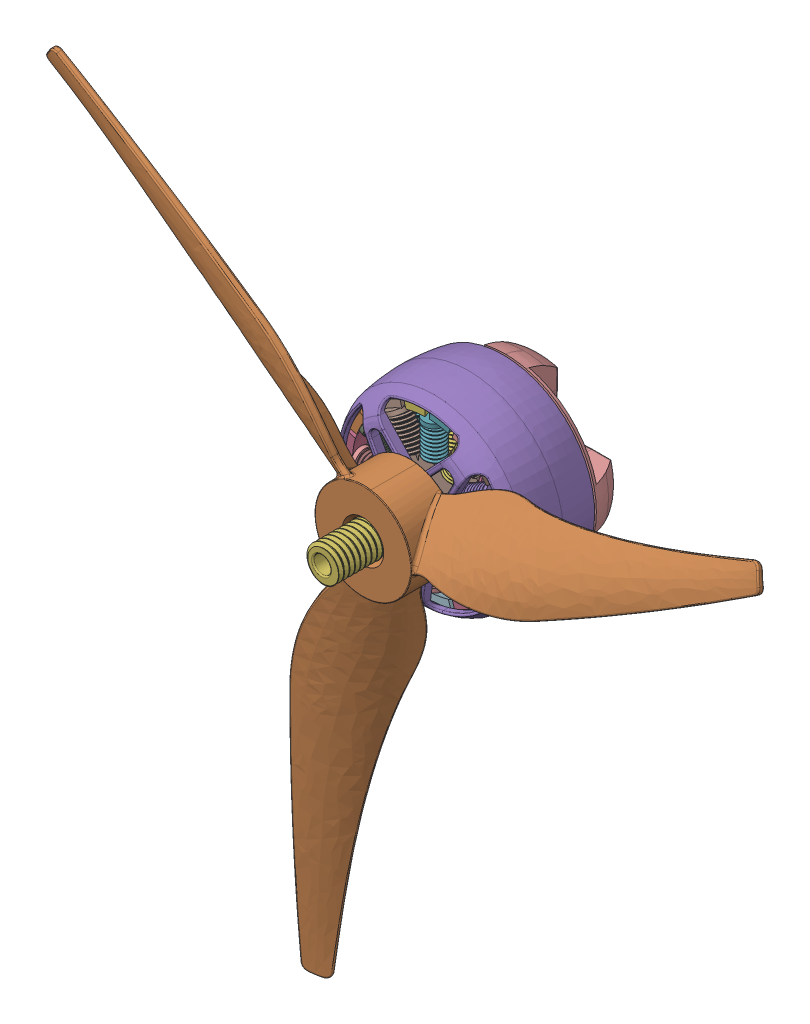
SolidWorks assembly Propeller unit, configuration Default. Lengths in mm.
Overall size (119.26 107.59 31.4).
2 component instances, 2 part files, 2 mates.
Components (placement in the parent):
- brushless emax series eco ii 2207 v23-1: brushless emax series eco ii 2207 v23 [Default] at (-7.3815 5.1684 -33.164) size (27.5 27.5 31.4)
- gemfan propeller 51466-1: gemfan propeller 51466 [Default] at (-7.3815 5.1684 -16.264) x (0.988508 -0.151167 0) z (-0.151167 -0.988508 0) size (106.5 9.65 92.55)
Mates (geometry in assembly coordinates):
- Concentric2: concentric anti-aligned: cylinder of brushless emax series eco ii 2207 v23-1 through (-7.3815 5.1684 -19.864) axis (0 0 1) radius 2.4505; cylinder of gemfan propeller 51466-1 through (-7.3815 5.1684 -12.864) axis (0 0 -1) radius 2.5
- Coincident2: coincident anti-aligned: plane of brushless emax series eco ii 2207 v23-1 through (-7.3815 5.1753 -19.664) normal (0 0 1); plane of gemfan propeller 51466-1 through (-7.3815 5.1684 -19.664) normal (0 0 -1)
